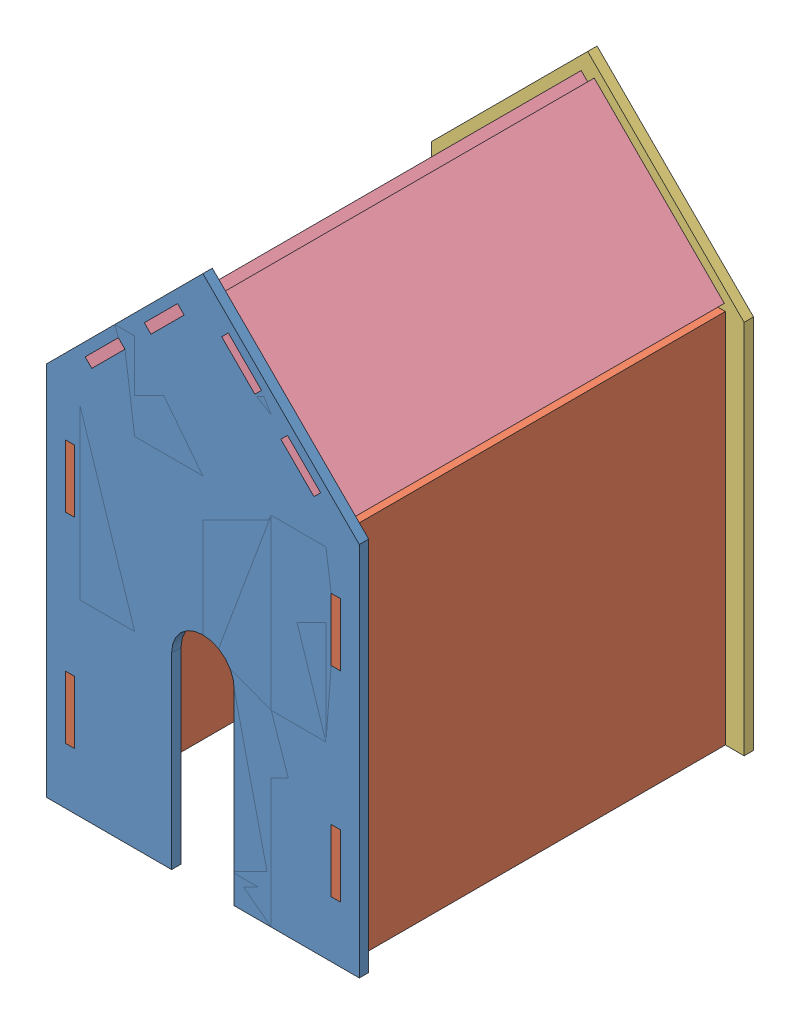
SolidWorks assembly casa perro ensamble1, configuration Predeterminado. Lengths in mm.
Overall size (500 850 630).
7 component instances, 4 part files, 22 mates.
Components (placement in the parent):
- parte atras casa de perro-1: parte atras casa de perro [Predeterminado] at origin size (500 850 15) (hidden)
- parte lateral casa de perro-1: parte lateral casa de perro [Predeterminado] at (45 0 -600) x (0 0 1) z (-1 0 0) size (630 600 15)
- parte delante casa perro-1: parte delante casa perro [Predeterminado] at (0 0 -615) size (500 850 15)
- techo casa de perro-2: techo casa de perro [Predeterminado] at (31.6444 610.4312 0) x (0 0 -1) z (0.707107 -0.707107 0) size (630 294.05 15)
- parte lateral casa de perro-2: parte lateral casa de perro [Predeterminado] at (470 0 -600) x (0 0 1) z (-1 0 0) size (630 600 15)
- parte atras casa de perro-2: parte atras casa de perro [Predeterminado] at origin size (500 850 15)
- techo casa de perro-6: techo casa de perro [Predeterminado] at (468.356 610.4308 -600) x (0 0 1) z (-0.707107 -0.707107 0) size (630 294.05 15)
Mates (geometry in assembly coordinates):
- Coincident1: coincident anti-aligned: plane of parte atras casa de perro-1 through (45 0 15) normal (-1 0 0); plane of parte lateral casa de perro-1 through (45 0 -600) normal (1 0 0)
- Coincident2: coincident anti-aligned: plane of parte atras casa de perro-1 through (0 510 15) normal (0 -1 0); plane of parte lateral casa de perro-1 through (30 510 0) normal (0 1 0)
- Coincident3: coincident anti-aligned: plane of parte atras casa de perro-1 through (45 0 15) normal (-1 0 0); plane of parte lateral casa de perro-1 through (45 0 -600) normal (1 0 0)
- Coincident4: coincident: line of parte atras casa de perro-1 through (45 410 15) axis (0 1 0); plane of parte lateral casa de perro-1 through (30 510 15) normal (0 0 1)
- Coincident9: coincident anti-aligned: plane of parte lateral casa de perro-1 through (30 0 -600) normal (-1 0 0); plane of parte delante casa perro-1 through (30 0 -600) normal (1 0 0)
- Coincident10: coincident aligned: plane of parte lateral casa de perro-1 through (30 510 -615) normal (0 0 -1); plane of parte delante casa perro-1 through (0 0 -615) normal (0 0 -1)
- Coincident16: coincident aligned: plane of parte atras casa de perro-1 through (0 0 15) normal (0 0 1); plane of techo casa de perro-2 through (72.4268 630.0004 15) normal (0 0 1)
- Coincident17: coincident anti-aligned: plane of parte atras casa de perro-1 through (-278.7868 278.7868 15) normal (-0.707107 0.707107 0); plane of techo casa de perro-2 through (42.251 599.8246 0) normal (0.707107 -0.707107 0)
- Coincident21: coincident anti-aligned: plane of parte atras casa de perro-1 through (498.7868 498.7868 15) normal (-0.707107 -0.707107 0); plane of techo casa de perro-2 through (220 777.5736 15) normal (0.707107 0.707107 0)
- Coincident22: coincident anti-aligned: plane of parte delante casa perro-1 through (-289.3934 289.3934 -600) normal (0.707107 -0.707107 0); plane of techo casa de perro-2 through (31.6444 610.4312 0) normal (-0.707107 0.707107 0)
- Coincident23: coincident anti-aligned: plane of parte delante casa perro-1 through (455 0 -600) normal (1 0 0); plane of parte lateral casa de perro-2 through (455 0 -600) normal (-1 0 0)
- Coincident24: coincident anti-aligned: plane of parte delante casa perro-1 through (0 510 -600) normal (0 -1 0); plane of parte lateral casa de perro-2 through (455 510 -615) normal (0 1 0)
- Coincident25: coincident aligned: plane of parte delante casa perro-1 through (0 0 -615) normal (0 0 -1); plane of parte lateral casa de perro-2 through (455 510 -615) normal (0 0 -1)
- Coincident49: coincident aligned: plane of parte lateral casa de perro-2 through (455 90 15) normal (0 0 1); plane of parte atras casa de perro-2 through (0 0 15) normal (0 0 1)
- Coincident50: coincident anti-aligned: plane of parte lateral casa de perro-2 through (455 0 0) normal (0 0 1); plane of parte atras casa de perro-2 through (0 0 0) normal (0 0 -1)
- Coincident51: coincident aligned: plane of parte lateral casa de perro-1 through (30 90 15) normal (0 0 1); plane of parte atras casa de perro-2 through (0 0 15) normal (0 0 1)
- Coincident52: coincident aligned: plane of techo casa de perro-2 through (166.967 724.5406 15) normal (0 0 1); plane of parte atras casa de perro-2 through (0 0 15) normal (0 0 1)
- Coincident53: coincident anti-aligned: plane of techo casa de perro-2 through (166.967 724.5406 0) normal (-0.707107 -0.707107 0); plane of parte atras casa de perro-2 through (445.7538 445.7538 15) normal (0.707107 0.707107 0)
- Coincident54: coincident anti-aligned: plane of parte lateral casa de perro-1 through (30 0 -600) normal (-1 0 0); plane of parte atras casa de perro-2 through (30 0 15) normal (1 0 0)
- Coincident76: coincident aligned: plane of parte atras casa de perro-2 through (0 0 15) normal (0 0 1); plane of techo casa de perro-6 through (427.5736 630 15) normal (0 0 1)
- Coincident77: coincident anti-aligned: plane of parte atras casa de perro-2 through (539.3934 539.3934 15) normal (-0.707107 -0.707107 0); plane of techo casa de perro-6 through (468.356 610.4308 -600) normal (0.707107 0.707107 0)
- Coincident78: coincident anti-aligned: plane of parte atras casa de perro-2 through (-154.2462 154.2462 15) normal (0.707107 -0.707107 0); plane of techo casa de perro-6 through (374.5406 683.033 15) normal (-0.707107 0.707107 0)
